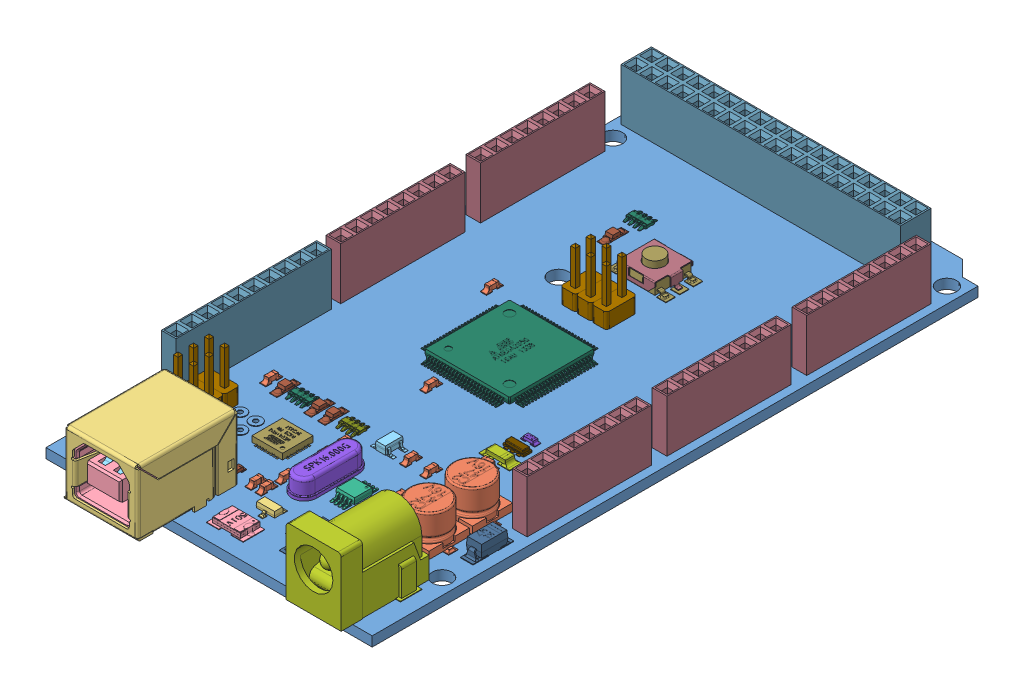
SolidWorks assembly arduino MEGA2650, configuration Default. Lengths in mm.
Overall size (53.34 15.25 107.99).
69 component instances, 33 part files, 170 mates.
Components (placement in the parent):
- MEGAboard-1: MEGAboard [Default] at origin size (53.34 1.6 101.6)
- 47uf CAP Dcase-1: 47uf CAP Dcase [Default] at (-9.144 0 -18.415) x (0 0 -1) z (1 0 0) size (6.6 5.81 8)
- USB type b-1: USB type b [Default] at (-38.02 0.43 6.35) size (14.34 15.2 16.54)
  - USB SHELL-1: USB SHELL [Default] at origin size (14.34 15.2 16.54)
  - USB core-1: USB core [Default] at origin size (11.3 10.68 15.75)
  - usb top contact-1: usb top contact [Default] at (1.25 6.09 -0.38) size (1 9.67 13.76)
  - usb btm contact-1: usb btm contact [Default] at (1.25 4.41 -0.38) size (1 6.84 11.76)
  - usb btm contact-2: usb btm contact [Default] at (-1.25 4.41 -0.38) size (1 6.84 11.76)
  - usb top contact-2: usb top contact [Default] at (-1.25 6.09 -0.38) size (1 9.67 13.76)
- power jack-1: power jack [Default] at (-7.675 0 1.905) size (11.2 15.2 15.9)
- 47uf CAP Dcase-2: 47uf CAP Dcase [Default] at (-9.144 0 -25.527) x (0 0 -1) z (1 0 0) size (6.6 5.81 8)
- crystal-1: crystal [Default] at (-26.035 0 -18.415) x (1 0 0) z (0 0 -1) size (4 5 11)
- 2pin_header__02-1: 2pin_header__02 [Default] at (-46.23 0 -15.75) size (5 11.75 2.54)
- reg-1: reg [Default] at (-17.78 0 -8.636) size (6.5 1.69 8.3)
- led-1: led [Default] at (-34.29 0 -27.94) x (0 0 1) z (-1 0 0) size (4 0.86 1.35)
- 2pin_header__02-2: 2pin_header__02 [Default] at (-30.43 0 -64.91) x (0 0 1) z (-1 0 0) size (5 11.75 2.54)
- 2pin_header__02-3: 2pin_header__02 [Default] at (-27.89 0 -64.91) x (0 0 1) z (-1 0 0) size (5 11.75 2.54)
- 2pin_header__02-4: 2pin_header__02 [Default] at (-25.35 0 -64.91) x (0 0 1) z (-1 0 0) size (5 11.75 2.54)
- 2pin_header__02-5: 2pin_header__02 [Default] at (-46.23 0 -18.29) size (5 11.75 2.54)
- 2pin_header__02-6: 2pin_header__02 [Default] at (-46.23 0 -20.83) size (5 11.75 2.54)
- atmega16u2-1: atmega16u2 [Default] at (-34.671 0.06 -20) x (1 0 0) z (0 0 -1) size (5.5 1.01 5.5)
- led-2: led [Default] at (-36.576 0 -27.94) x (0 0 -1) z (1 0 0) size (4 0.86 1.35)
- led-3: led [Default] at (-42.164 0 -27.94) x (0 0 1) z (-1 0 0) size (4 0.86 1.35)
- led-4: led [Default] at (-36.83 0 -76.2) x (0 0 1) z (-1 0 0) size (4 0.86 1.35)
- 8 PORT HEADER-3: 8 PORT HEADER [Default] at (-50.8 0 -45.72) x (0 0 -1) z (1 0 0) size (20.32 10.51 2.41)
- 8 PORT HEADER-4: 8 PORT HEADER [Default] at (-2.54 0 -27.94) x (0 0 -1) z (1 0 0) size (20.32 10.51 2.41)
- 8 PORT HEADER-6: 8 PORT HEADER [Default] at (-2.54 0 -50.8) x (0 0 -1) z (1 0 0) size (20.32 10.51 2.41)
- 10 PORT HEADER-1: 10 PORT HEADER [Default] at (-50.8 0 -18.796) x (0 0 -1) z (1 0 0) size (25.4 10.51 2.41)
- 102 RESISTOR PACK-1: 102 RESISTOR PACK [Default] at (-36.83 0 -80.645) size (3.2 0.46 3)
- 102 RESISTOR PACK-2: 102 RESISTOR PACK [Default] at (-39.37 0 -27.94) size (3.2 0.46 3)
- 103 RESISTOR PACK-3: 103 RESISTOR PACK [Default] at (-31.115 0 -27.94) size (3.2 0.46 3)
- 220 RESISTOR PACK-1: 220 RESISTOR PACK [Default] at (-37.084 0 -12.065) size (3.2 0.46 3)
- 16mhz crystal - measured-1: 16mhz crystal - measured [Default] at (-14.605 0 -38.354) size (3.4 0.8 2)
- PADS001-1: PADS001 [Default] at (-39.878 0.1 -18.288) x (-1 0 0) z (0 0 1) size (4.54 0.1 4.54)
- 603 cap on pad-1: 603 cap on pad [Default] at (-44.45 0 -27.94) x (0 0 -1) z (1 0 0) size (2.76 0.9 1.12)
- ssot3-1: ssot3 [Default] at (-25.908 0 -9.144) x (-1 0 0) z (0 0 -1) size (3 1.13 3.09)
- mf-msmf050-2-1: mf-msmf050-2 [Default] at (-26.67 0 -4.445) size (5.77 1.02 3.72)
- 603 cap on pad-2: 603 cap on pad [Default] at (-29.337 0 -24.765) x (0 0 1) z (-1 0 0) size (2.76 0.9 1.12)
- 603 cap on pad-3: 603 cap on pad [Default] at (-30.988 0 -12.065) x (0 0 -1) z (1 0 0) size (2.76 0.9 1.12)
- lmv358-1: lmv358 [Default] at (-25.146 0 -27.94) size (3.7 1.4 2.9)
- 603 cap on pad-4: 603 cap on pad [Default] at (-17.653 0 -14.351) size (2.76 0.9 1.12)
- 603 cap on pad-5: 603 cap on pad [Default] at (-29.337 0 -12.065) x (0 0 1) z (-1 0 0) size (2.76 0.9 1.12)
- 603 cap on pad-6: 603 cap on pad [Default] at (-29.337 0 -21.59) x (0 0 1) z (-1 0 0) size (2.76 0.9 1.12)
- 603 cap on pad-7: 603 cap on pad [Default] at (-29.337 0 -15.24) x (0 0 1) z (-1 0 0) size (2.76 0.9 1.12)
- 603 cap on pad-8: 603 cap on pad [Default] at (-42.291 0 -12.065) x (0 0 1) z (-1 0 0) size (2.76 0.9 1.12)
- lp2985dgkr-1: lp2985dgkr [Default] at (-21.336 0 -18.415) x (0 0 -1) z (1 0 0) size (5.85 1.1 3)
- cd1206 diode-1: cd1206 diode [Default] at (-14.605 0 -35.56) x (0 0 1) z (-1 0 0) size (2.07 0.96 5)
- cd1206 diode-2: cd1206 diode [Default] at (-46.228 0 -13.081) x (0 0 1) z (-1 0 0) size (2.07 0.96 5)
- 603 resistor-1: 603 resistor [Default] at (-29.337 0 -18.415) x (0 0 1) z (-1 0 0) size (2.36 0.61 1.03)
- blm21-1: blm21 [Default] at (-45.085 0 -8.255) x (0 0 -1) z (1 0 0) size (2.76 0.95 1.32)
- m7 diode-1: m7 diode [Default] at (-2.794 0 -21.59) x (0 0 -1) z (1 0 0) size (6.66 2.35 2.5)
- MLC0603-1: MLC0603 [Default] at (-34.29 0 -12.065) x (0 0 -1) z (1 0 0) size (2.36 0.6 1.03)
- MLC0603-2: MLC0603 [Default] at (-39.878 0 -12.065) x (0 0 -1) z (1 0 0) size (2.36 0.6 1.03)
- RESET BUTTON-1: RESET BUTTON [Default] at (-27.94 0 -74.168) x (0 0 -1) z (1 0 0) size (6.2 3.1 9.6)
  - RESET CORE-1: RESET CORE [Default] at (0 0.1 0) x (-1 0 0) z (0 0 -1) size (6.2 3.1 9.6)
  - RESET-1: RESET [Default] at (0 0.1 0) x (0 0 1) z (-1 0 0) size (7.3 2 6.2)
- 8 PORT HEADER-5: 8 PORT HEADER [Default] at (-2.54 0 -73.66) x (0 0 -1) z (1 0 0) size (20.32 10.51 2.41)
- 8 PORT HEADER-7: 8 PORT HEADER [Default] at (-50.8 0 -68.58) x (0 0 -1) z (1 0 0) size (20.32 10.51 2.41)
- 603 cap on pad-9: 603 cap on pad [Default] at (-21.59 0 -27.94) x (0 0 1) z (-1 0 0) size (2.76 0.9 1.12)
- 603 cap on pad-10: 603 cap on pad [Default] at (-18.288 0 -27.94) x (0 0 1) z (-1 0 0) size (2.76 0.9 1.12)
- 103 RESISTOR PACK-4: 103 RESISTOR PACK [Default] at (-16.51 0 -18.415) size (3.2 0.46 3)
- 603 cap on pad-11: 603 cap on pad [Default] at (-17.145 0 -21.59) x (0 0 -1) z (1 0 0) size (2.76 0.9 1.12)
- 603 cap on pad-12: 603 cap on pad [Default] at (-39.37 0 -58.928) x (0 0 1) z (-1 0 0) size (2.76 0.9 1.12)
- 603 cap on pad-13: 603 cap on pad [Default] at (-14.605 0 -33.528) size (2.76 0.9 1.12)
- 603 resistor-2: 603 resistor [Default] at (-14.605 0 -40.513) x (-1 0 0) z (0 0 -1) size (2.36 0.61 1.03)
- 603 cap on pad-14: 603 cap on pad [Default] at (-7.112 0 -38.608) x (0 0 1) z (-1 0 0) size (2.76 0.9 1.12)
- 603 cap on pad-15: 603 cap on pad [Default] at (-30.4038 0 -40.0558) x (0 0 1) z (-1 0 0) size (2.76 0.9 1.12)
- 18 X 2 ROW HEADER-1: 18 X 2 ROW HEADER [Default] at (-50.8 0 -95.25) size (45.72 10.51 4.95)
- atmega2650-16AU-1: atmega2650-16AU [Default] at (-28.3464 0.1 -50.8) x (0 0 1) z (-1 0 0) size (16.8 1.1 16.8)
Mates (geometry in assembly coordinates):
- Distance1: distance = 1.905 mm aligned: plane of power jack-1 through (-7.675 0 1.905) normal (0 0 1); plane of MEGAboard-1 through (0 0 0) normal (0 0 1)
- Coincident2: coincident aligned: plane of MEGAboard-1 through (0 0 0) normal (0 1 0); plane of power jack-1 through (-7.675 0 1.905) normal (0 1 0)
- Coincident3: coincident anti-aligned: plane of MEGAboard-1 through (0 0 0) normal (0 1 0); plane of USB type b-1/USB core-1 through (-38.02 0 6.35) normal (0 -1 0)
- Distance2: distance = 6.35 mm aligned: plane of USB type b-1/USB SHELL-1 through (-38.02 0.43 6.35) normal (0 0 1); plane of MEGAboard-1 through (0 0 0) normal (0 0 1)
- Coincident5: coincident aligned: plane of MEGAboard-1 through (0 0 0) normal (0 1 0); plane of 47uf CAP Dcase-1
- Parallel1: parallel anti-aligned: plane of MEGAboard-1 through (0 0 0) normal (0 0 1); plane of 47uf CAP Dcase-1 through (-9.144 0 -18.415) normal (0 0 -1)
- Coincident7: coincident aligned: plane of 47uf CAP Dcase-1 through (-5.844 1.5 -15.115) normal (1 0 0); plane of 47uf CAP Dcase-2 through (-5.844 1.5 -22.227) normal (1 0 0)
- Coincident8: coincident anti-aligned: plane of MEGAboard-1 through (0 0 0) normal (0 1 0); plane of 47uf CAP Dcase-2 through (-7.919 0 -25.527) normal (0 -1 0)
- Distance3: distance = 3.175 mm aligned: plane of power jack-1 through (-3.175 10.5 -1.595) normal (1 0 0); plane of MEGAboard-1 through (0 -1.6 0) normal (1 0 0)
- Distance4: distance = 32 mm aligned: plane of USB type b-1/USB SHELL-1 through (-32 0.43 6.35) normal (1 0 0); plane of MEGAboard-1 through (0 -1.6 0) normal (1 0 0)
- Coincident11: coincident anti-aligned: plane of MEGAboard-1 through (0 0 0) normal (0 1 0); plane of crystal-1 through (-26.035 0 -21.915) normal (0 -1 0)
- Concentric1: concentric aligned: cylinder of MEGAboard-1 through (-26.035 -10 -15.875) axis (0 1 0) radius 0.5; cylinder of crystal-1 through (-26.035 -2 -15.875) axis (0 1 0) radius 0.4
- Concentric2: concentric aligned: cylinder of MEGAboard-1 through (-26.035 -10 -20.955) axis (0 1 0) radius 0.5; cylinder of crystal-1 through (-26.035 -2 -20.955) axis (0 1 0) radius 0.4
- Coincident12: coincident anti-aligned: plane of MEGAboard-1 through (0 0 0) normal (0 1 0); plane of 2pin_header__02-1 through (-44.23 0 -14.98) normal (0 -1 0)
- Distance5: distance = 15.75 mm aligned: plane of 2pin_header__02-1 through (-46.23 0 -15.75) normal (0 0 1); plane of assembly through (0 0 0) normal (0 0 1)
- Distance6: distance = 46.23 mm aligned: plane of 2pin_header__02-1 through (-46.23 0 -15.75) normal (1 0 0); plane of assembly through (0 0 0) normal (1 0 0)
- Coincident15: coincident anti-aligned: plane of MEGAboard-1 through (0 0 0) normal (0 1 0); plane of 2pin_header__02-2 through (-31.2 0 -62.91) normal (0 -1 0)
- Distance7: distance = 64.91 mm aligned: plane of 2pin_header__02-2 through (-30.43 0 -64.91) normal (0 0 1); plane of assembly through (0 0 0) normal (0 0 1)
- Distance8: distance = 30.43 mm anti-aligned: plane of 2pin_header__02-2 through (-30.43 0 -64.91) normal (-1 0 0); plane of assembly through (0 0 0) normal (1 0 0)
- Coincident19: coincident anti-aligned: plane of MEGAboard-1 through (0 0 0) normal (0 1 0); plane of reg-1 through (-17.78 0 -8.636) normal (0 -1 0)
- Coincident21: coincident anti-aligned: plane of MEGAboard-1 through (0 0 0) normal (0 1 0); plane of atmega16u2-1 through (-34.671 0 -20) normal (0 -1 0)
- Distance10: distance = 20 mm anti-aligned: plane of atmega16u2-1 through (-34.671 0.06 -20) normal (0 0 -1); plane of MEGAboard-1 through (0 0 0) normal (0 0 1)
- Distance11: distance = 34.671 mm aligned: plane of atmega16u2-1; plane of MEGAboard-1 through (0 0 0) normal (1 0 0)
- Coincident25: coincident anti-aligned: plane of MEGAboard-1 through (0 0 0) normal (0 1 0); plane of led-1 through (-34.29 0 -28.94) normal (0 -1 0)
- Distance12: distance = 34.29 mm anti-aligned: plane of led-1 through (-34.29 0 -27.94) normal (-1 0 0); plane of MEGAboard-1 through (0 0 0) normal (1 0 0)
- Distance13: distance = 27.94 mm aligned: plane of led-1 through (-34.29 0 -27.94) normal (0 0 1); plane of MEGAboard-1 through (0 0 0) normal (0 0 1)
- Coincident28: coincident aligned: plane of led-2 through (-36.576 0 -26.94) normal (0 -1 0); plane of led-3 through (-42.164 0 -28.94) normal (0 -1 0)
- Coincident29: coincident anti-aligned: plane of led-1 through (-34.29 0 -27.94) normal (0 0 1); plane of led-2 through (-36.576 0 -27.94) normal (0 0 -1)
- Coincident30: coincident aligned: plane of led-1 through (-34.29 0 -27.94) normal (0 0 1); plane of led-3 through (-42.164 0 -27.94) normal (0 0 1)
- Distance14: distance = 36.576 mm aligned: plane of led-2 through (-36.576 0 -27.94) normal (1 0 0); plane of MEGAboard-1 through (0 0 0) normal (1 0 0)
- Coincident32: coincident anti-aligned: plane of MEGAboard-1 through (0 0 0) normal (0 1 0); plane of led-2 through (-36.576 0 -26.94) normal (0 -1 0)
- Distance15: distance = 42.164 mm anti-aligned: plane of led-3 through (-42.164 0 -27.94) normal (-1 0 0); plane of MEGAboard-1 through (0 0 0) normal (1 0 0)
- Coincident34: coincident anti-aligned: plane of MEGAboard-1 through (0 0 0) normal (0 1 0); plane of led-4 through (-36.83 0 -77.2) normal (0 -1 0)
- Distance16: distance = 36.83 mm anti-aligned: plane of led-4 through (-36.83 0 -76.2) normal (-1 0 0); plane of MEGAboard-1 through (0 0 0) normal (1 0 0)
- Distance17: distance = 76.2 mm aligned: plane of led-4 through (-36.83 0 -76.2) normal (0 0 1); plane of MEGAboard-1 through (0 0 0) normal (0 0 1)
- Coincident37: coincident aligned: plane of MEGAboard-1 through (0 0 0) normal (0 1 0); plane of 8 PORT HEADER-4
- Coincident38: coincident aligned: plane of MEGAboard-1 through (0 0 0) normal (0 1 0); plane of 8 PORT HEADER-3
- Parallel2: parallel aligned: plane of MEGAboard-1 through (0 0 0) normal (1 0 0); plane of 8 PORT HEADER-4 through (-2.54 0 -27.94) normal (1 0 0)
- Parallel3: parallel aligned: plane of MEGAboard-1 through (0 0 0) normal (1 0 0); plane of 8 PORT HEADER-3 through (-50.8 0 -45.72) normal (1 0 0)
- Concentric5: concentric aligned: cylinder of MEGAboard-1 through (-2.54 -1.65 -27.94) axis (0 1 0) radius 0.4; line of 8 PORT HEADER-4 through (-2.54 -2.5255 -27.94) axis (0 1 0)
- Concentric6: concentric aligned: cylinder of MEGAboard-1 through (-50.8 -1.65 -45.72) axis (0 1 0) radius 0.4; line of 8 PORT HEADER-3 through (-50.8 -2.5255 -45.72) axis (0 1 0)
- Coincident43: coincident aligned: plane of MEGAboard-1 through (0 0 0) normal (0 1 0); plane of 10 PORT HEADER-1
- Coincident44: coincident aligned: plane of MEGAboard-1 through (0 0 0) normal (0 1 0); plane of 8 PORT HEADER-6
- Parallel4: parallel aligned: plane of MEGAboard-1 through (0 0 0) normal (1 0 0); plane of 8 PORT HEADER-6 through (-2.54 0 -50.8) normal (1 0 0)
- Parallel5: parallel aligned: plane of MEGAboard-1 through (0 0 0) normal (1 0 0); plane of 10 PORT HEADER-1 through (-50.8 0 -18.796) normal (1 0 0)
- Concentric7: concentric aligned: cylinder of MEGAboard-1 through (-50.8 -1.65 -18.796) axis (0 1 0) radius 0.4; line of 10 PORT HEADER-1 through (-50.8 -2.5255 -18.796) axis (0 1 0)
- Concentric9: concentric aligned: cylinder of MEGAboard-1 through (-2.54 -1.65 -50.8) axis (0 1 0) radius 0.4; line of 8 PORT HEADER-6 through (-2.54 -2.5255 -50.8) axis (0 1 0)
- Distance18: distance = 8.636 mm: plane of reg-1 through (-17.78 0 -8.636) normal (0 0 1); line of MEGAboard-1 through (-53.34 0 0) axis (1 0 0)
- Distance19: distance = 17.78 mm aligned: plane of reg-1 through (-17.78 0 -8.636) normal (1 0 0); plane of MEGAboard-1 through (0 0 0) normal (1 0 0)
- Coincident55: coincident anti-aligned: plane of MEGAboard-1 through (0 0 0) normal (0 1 0); plane of 102 RESISTOR PACK-1 through (-37.03 0 -81.345) normal (0 -1 0)
- Distance20: distance = 36.83 mm aligned: plane of 102 RESISTOR PACK-1 through (-36.83 0 -80.645) normal (1 0 0); plane of MEGAboard-1 through (0 0 0) normal (1 0 0)
- Distance21: distance = 80.645 mm aligned: plane of 102 RESISTOR PACK-1 through (-36.83 0 -80.645) normal (0 0 1); plane of MEGAboard-1 through (0 0 0) normal (0 0 1)
- Coincident58: coincident aligned: plane of 102 RESISTOR PACK-2 through (-39.37 0 -27.94) normal (0 1 0); plane of 103 RESISTOR PACK-3 through (-31.115 0 -27.94) normal (0 1 0)
- Coincident59: coincident aligned: plane of MEGAboard-1 through (0 0 0) normal (0 1 0); plane of 103 RESISTOR PACK-3 through (-31.115 0 -27.94) normal (0 1 0)
- Coincident60: coincident aligned: plane of 102 RESISTOR PACK-2 through (-39.37 0 -27.94) normal (0 0 1); plane of 103 RESISTOR PACK-3 through (-31.115 0 -27.94) normal (0 0 1)
- Distance22: distance = 31.115 mm aligned: plane of 103 RESISTOR PACK-3 through (-31.115 0 -27.94) normal (1 0 0); plane of MEGAboard-1 through (0 0 0) normal (1 0 0)
- Distance23: distance = 39.37 mm aligned: plane of 102 RESISTOR PACK-2 through (-39.37 0 -27.94) normal (1 0 0); plane of MEGAboard-1 through (0 0 0) normal (1 0 0)
- Distance24: distance = 27.94 mm aligned: plane of 102 RESISTOR PACK-2 through (-39.37 0 -27.94) normal (0 0 1); plane of MEGAboard-1 through (0 0 0) normal (0 0 1)
- Distance25: distance = 12.065 mm aligned: plane of 220 RESISTOR PACK-1 through (-37.084 0 -12.065) normal (0 0 1); plane of MEGAboard-1 through (0 0 0) normal (0 0 1)
- Distance26: distance = 37.084 mm aligned: plane of 220 RESISTOR PACK-1 through (-37.084 0 -12.065) normal (1 0 0); plane of MEGAboard-1 through (0 0 0) normal (1 0 0)
- Coincident66: coincident aligned: plane of MEGAboard-1 through (0 0 0) normal (0 1 0); plane of 220 RESISTOR PACK-1 through (-37.084 0 -12.065) normal (0 1 0)
- Coincident67: coincident anti-aligned: plane of MEGAboard-1 through (0 0 0) normal (0 1 0); plane of 16mhz crystal - measured-1 through (-14.605 0 -38.354) normal (0 -1 0)
- Distance27: distance = 14.605 mm aligned: plane of 16mhz crystal - measured-1 through (-14.605 0 -38.354) normal (1 0 0); plane of MEGAboard-1 through (0 0 0) normal (1 0 0)
- Distance28: distance = 38.354 mm aligned: plane of 16mhz crystal - measured-1 through (-14.605 0 -38.354) normal (0 0 1); plane of MEGAboard-1 through (0 0 0) normal (0 0 1)
- Coincident70: coincident anti-aligned: plane of MEGAboard-1 through (0 0 0) normal (0 1 0); plane of PADS001-1 through (-42.418 0 -18.288) normal (0 -1 0)
- Distance29: distance = 18.288 mm aligned: plane of PADS001-1 through (-39.878 0.1 -18.288) normal (0 0 1); plane of MEGAboard-1 through (0 0 0) normal (0 0 1)
- Distance30: distance = 39.878 mm anti-aligned: plane of PADS001-1; plane of MEGAboard-1 through (0 0 0) normal (1 0 0)
- Distance31: distance = 4.445 mm aligned: plane of mf-msmf050-2-1 through (-26.67 0 -4.445) normal (0 0 1); plane of MEGAboard-1 through (0 0 0) normal (0 0 1)
- Distance32: distance = 26.67 mm aligned: plane of mf-msmf050-2-1 through (-26.67 0 -4.445) normal (1 0 0); plane of MEGAboard-1 through (0 0 0) normal (1 0 0)
- Coincident72: coincident aligned: plane of MEGAboard-1 through (0 0 0) normal (0 1 0); plane of mf-msmf050-2-1 through (-26.67 0 -4.445) normal (0 1 0)
- Distance33: distance = 9.144 mm anti-aligned: plane of MEGAboard-1 through (0 0 0) normal (0 0 1); plane of ssot3-1 through (-25.908 0 -9.144) normal (0 0 -1)
- Distance78: distance = 0.762 mm anti-aligned: plane of ssot3-1 through (-25.908 0 -9.144) normal (-1 0 0); plane of mf-msmf050-2-1 through (-26.67 0 -4.445) normal (1 0 0)
- Coincident75: coincident aligned: plane of MEGAboard-1 through (0 0 0) normal (0 1 0); plane of ssot3-1
- Coincident76: coincident anti-aligned: plane of led-1 through (-34.29 0 -27.94) normal (0 0 1); plane of 603 cap on pad-1 through (-44.45 0 -27.94) normal (0 0 -1)
- Coincident77: coincident aligned: plane of MEGAboard-1 through (0 0 0) normal (0 1 0); plane of 603 cap on pad-1
- Distance34: distance = 44.45 mm aligned: plane of 603 cap on pad-1 through (-44.45 0 -27.94) normal (1 0 0); plane of MEGAboard-1 through (0 0 0) normal (1 0 0)
- Coincident79: coincident aligned: plane of 603 cap on pad-2; plane of 603 cap on pad-3
- Coincident81: coincident aligned: plane of MEGAboard-1 through (0 0 0) normal (0 1 0); plane of 603 cap on pad-2
- Distance65: distance = 24.765 mm aligned: plane of 603 cap on pad-2 through (-29.337 0 -24.765) normal (0 0 1); plane of MEGAboard-1 through (0 0 0) normal (0 0 1)
- Distance36: distance = 29.337 mm anti-aligned: plane of 603 cap on pad-2 through (-29.337 0 -24.765) normal (-1 0 0); plane of MEGAboard-1 through (0 0 0) normal (1 0 0)
- Distance37: distance = 30.988 mm aligned: plane of 603 cap on pad-3 through (-30.988 0 -12.065) normal (1 0 0); plane of MEGAboard-1 through (0 0 0) normal (1 0 0)
- Distance38: distance = 27.94 mm aligned: plane of MEGAboard-1 through (0 0 0) normal (0 0 1); plane of lmv358-1 through (-25.146 0 -27.94) normal (0 0 1)
- Distance39: distance = 21.971 mm anti-aligned: plane of ?; plane of MEGAboard-1 through (0 0 0) normal (0 0 1)
- Coincident88: coincident aligned: plane of MEGAboard-1 through (0 0 0) normal (0 1 0); plane of lmv358-1 through (-25.146 0 -27.94) normal (0 1 0)
- Distance40: distance = 14.351 mm aligned: plane of 603 cap on pad-4 through (-17.653 0 -14.351) normal (0 0 1); plane of MEGAboard-1 through (0 0 0) normal (0 0 1)
- Distance41: distance = 17.653 mm aligned: plane of 603 cap on pad-4 through (-17.653 0 -14.351) normal (1 0 0); plane of MEGAboard-1 through (0 0 0) normal (1 0 0)
- Coincident91: coincident aligned: plane of MEGAboard-1 through (0 0 0) normal (0 1 0); plane of 603 cap on pad-4 through (-17.653 0 -14.351) normal (0 1 0)
- Coincident92: coincident aligned: plane of MEGAboard-1 through (0 0 0) normal (0 1 0); plane of 603 cap on pad-7
- Coincident93: coincident aligned: plane of MEGAboard-1 through (0 0 0) normal (0 1 0); plane of 603 cap on pad-6
- Coincident94: coincident aligned: plane of 603 cap on pad-5; plane of MEGAboard-1 through (0 0 0) normal (0 1 0)
- Coincident95: coincident aligned: plane of 603 cap on pad-8; plane of MEGAboard-1 through (0 0 0) normal (0 1 0)
- Coincident96: coincident aligned: plane of 603 cap on pad-7 through (-29.337 0 -15.24) normal (-1 0 0); plane of 603 cap on pad-6 through (-29.337 0 -21.59) normal (-1 0 0)
- Distance42: distance = 29.337 mm anti-aligned: plane of 603 cap on pad-7 through (-29.337 0 -15.24) normal (-1 0 0); plane of MEGAboard-1 through (0 0 0) normal (1 0 0)
- Distance43: distance = 21.59 mm: plane of 603 cap on pad-6 through (-29.337 0 -21.59) normal (0 0 1); line of MEGAboard-1 through (-53.34 0 0) axis (1 0 0)
- Distance44: distance = 15.24 mm aligned: plane of 603 cap on pad-7 through (-29.337 0 -15.24) normal (0 0 1); plane of MEGAboard-1 through (0 0 0) normal (0 0 1)
- Distance45: distance = 29.337 mm anti-aligned: plane of 603 cap on pad-5 through (-29.337 0 -12.065) normal (-1 0 0); plane of MEGAboard-1 through (0 0 0) normal (1 0 0)
- Distance46: distance = 12.065 mm aligned: plane of 603 cap on pad-5 through (-29.337 0 -12.065) normal (0 0 1); plane of MEGAboard-1 through (0 0 0) normal (0 0 1)
- Distance47: distance = 42.291 mm anti-aligned: plane of 603 cap on pad-8 through (-42.291 0 -12.065) normal (-1 0 0); plane of MEGAboard-1 through (0 0 0) normal (1 0 0)
- Distance48: distance = 12.065 mm aligned: plane of 603 cap on pad-8 through (-42.291 0 -12.065) normal (0 0 1); plane of MEGAboard-1 through (0 0 0) normal (0 0 1)
- Distance49: distance = 21.336 mm aligned: plane of lp2985dgkr-1 through (-21.336 0 -18.415) normal (1 0 0); plane of MEGAboard-1 through (0 0 0) normal (1 0 0)
- Distance50: distance = 18.415 mm anti-aligned: plane of lp2985dgkr-1 through (-21.336 0 -18.415) normal (0 0 -1); plane of MEGAboard-1 through (0 0 0) normal (0 0 1)
- Coincident99: coincident aligned: plane of MEGAboard-1 through (0 0 0) normal (0 1 0); plane of lp2985dgkr-1
- Distance51: distance = 14.605 mm anti-aligned: plane of cd1206 diode-1 through (-14.605 0 -35.56) normal (-1 0 0); plane of MEGAboard-1 through (0 0 0) normal (1 0 0)
- Distance52: distance = 35.56 mm aligned: plane of cd1206 diode-1 through (-14.605 0 -35.56) normal (0 0 1); plane of MEGAboard-1 through (0 0 0) normal (0 0 1)
- Coincident102: coincident aligned: plane of MEGAboard-1 through (0 0 0) normal (0 1 0); plane of cd1206 diode-1
- Distance53: distance = 46.228 mm anti-aligned: plane of cd1206 diode-2 through (-46.228 0 -13.081) normal (-1 0 0); plane of MEGAboard-1 through (0 0 0) normal (1 0 0)
- Distance54: distance = 13.081 mm aligned: plane of MEGAboard-1 through (0 0 0) normal (0 0 1); plane of cd1206 diode-2 through (-46.228 0 -13.081) normal (0 0 1)
- Coincident105: coincident aligned: plane of MEGAboard-1 through (0 0 0) normal (0 1 0); plane of cd1206 diode-2
- Distance55: distance = 29.337 mm anti-aligned: plane of 603 resistor-1 through (-29.337 0 -18.415) normal (-1 0 0); plane of MEGAboard-1 through (0 0 0) normal (1 0 0)
- Distance56: distance = 18.415 mm aligned: plane of 603 resistor-1 through (-29.337 0 -18.415) normal (0 0 1); plane of MEGAboard-1 through (0 0 0) normal (0 0 1)
- Coincident108: coincident aligned: plane of MEGAboard-1 through (0 0 0) normal (0 1 0); plane of 603 resistor-1
- Distance57: distance = 8.255 mm anti-aligned: plane of blm21-1 through (-45.085 0 -8.255) normal (0 0 -1); plane of MEGAboard-1 through (0 0 0) normal (0 0 1)
- Distance58: distance = 45.085 mm aligned: plane of blm21-1 through (-45.085 0 -8.255) normal (1 0 0); plane of MEGAboard-1 through (0 0 0) normal (1 0 0)
- Distance59: distance = 21.59 mm anti-aligned: plane of m7 diode-1 through (-2.794 0 -21.59) normal (0 0 -1); plane of MEGAboard-1 through (0 0 0) normal (0 0 1)
- Distance60: distance = 2.794 mm aligned: plane of m7 diode-1 through (-2.794 0 -21.59) normal (1 0 0); plane of MEGAboard-1 through (0 0 0) normal (1 0 0)
- Coincident113: coincident aligned: plane of MEGAboard-1 through (0 0 0) normal (0 1 0); plane of m7 diode-1
- Coincident114: coincident anti-aligned: plane of 220 RESISTOR PACK-1 through (-37.084 0 -12.065) normal (0 0 1); plane of MLC0603-1 through (-34.29 0 -12.065) normal (0 0 -1)
- Distance61: distance = 34.29 mm aligned: plane of MLC0603-1 through (-34.29 0 -12.065) normal (1 0 0); plane of MEGAboard-1 through (0 0 0) normal (1 0 0)
- Coincident115: coincident aligned: plane of MEGAboard-1 through (0 0 0) normal (0 1 0); plane of MLC0603-1
- Coincident116: coincident aligned: plane of MEGAboard-1 through (0 0 0) normal (0 1 0); plane of blm21-1
- Coincident117: coincident anti-aligned: plane of 220 RESISTOR PACK-1 through (-37.084 0 -12.065) normal (0 0 1); plane of MLC0603-2 through (-39.878 0 -12.065) normal (0 0 -1)
- Coincident118: coincident aligned: plane of MEGAboard-1 through (0 0 0) normal (0 1 0); plane of MLC0603-2
- Distance62: distance = 39.878 mm aligned: plane of MLC0603-2 through (-39.878 0 -12.065) normal (1 0 0); plane of MEGAboard-1 through (0 0 0) normal (1 0 0)
- Coincident122: coincident aligned: plane of MEGAboard-1 through (0 0 0) normal (0 1 0); plane of RESET BUTTON-1
- Concentric10: concentric aligned: cylinder of MEGAboard-1 through (-2.54 -1.65 -73.66) axis (0 1 0) radius 0.4; line of 8 PORT HEADER-5 through (-2.54 -2.5255 -73.66) axis (0 1 0)
- Coincident124: coincident anti-aligned: plane of MEGAboard-1 through (0 0 0) normal (0 1 0); plane of 8 PORT HEADER-5 through (-2.54 0 -73.66) normal (0 -1 0)
- Parallel6: parallel aligned: plane of MEGAboard-1 through (0 0 0) normal (1 0 0); plane of 8 PORT HEADER-5 through (-1.335 8.51 -72.39) normal (1 0 0)
- Concentric11: concentric aligned: cylinder of MEGAboard-1 through (-50.8 -1.65 -68.58) axis (0 1 0) radius 0.4; line of 8 PORT HEADER-7 through (-50.8 -2.5255 -68.58) axis (0 1 0)
- Parallel7: parallel aligned: plane of MEGAboard-1 through (0 0 0) normal (1 0 0); plane of 8 PORT HEADER-7 through (-49.595 8.51 -67.31) normal (1 0 0)
- Coincident128: coincident anti-aligned: plane of MEGAboard-1 through (0 0 0) normal (0 1 0); plane of 8 PORT HEADER-7 through (-50.8 0 -68.58) normal (0 -1 0)
- Distance63: distance = 27.94 mm aligned: plane of RESET BUTTON-1; plane of MEGAboard-1 through (0 0 0) normal (1 0 0)
- Distance64: distance = 74.168 mm anti-aligned: plane of RESET BUTTON-1 through (-27.94 0 -74.168) normal (0 0 -1); plane of MEGAboard-1 through (0 0 0) normal (0 0 1)
- Coincident131: coincident anti-aligned: plane of 603 cap on pad-3 through (-30.988 0 -12.065) normal (0 0 -1); plane of 603 cap on pad-5 through (-29.337 0 -12.065) normal (0 0 1)
- Distance66: distance = 25.146 mm aligned: plane of lmv358-1 through (-25.146 0 -27.94) normal (1 0 0); plane of MEGAboard-1 through (0 0 0) normal (1 0 0)
- Distance67: distance = 9.144 mm aligned: plane of 47uf CAP Dcase-2 through (-9.144 0 -25.527) normal (1 0 0); plane of MEGAboard-1 through (0 0 0) normal (1 0 0)
- Distance68: distance = 25.527 mm anti-aligned: plane of 47uf CAP Dcase-2 through (-9.144 0 -25.527) normal (0 0 -1); plane of MEGAboard-1 through (0 0 0) normal (0 0 1)
- Distance69: distance = 18.415 mm anti-aligned: plane of 47uf CAP Dcase-1 through (-9.144 0 -18.415) normal (0 0 -1); plane of MEGAboard-1 through (0 0 0) normal (0 0 1)
- Coincident136: coincident aligned: plane of 603 cap on pad-9 through (-21.59 0 -27.94) normal (0 0 1); plane of 603 cap on pad-10 through (-18.288 0 -27.94) normal (0 0 1)
- Distance72: distance = 3.302 mm aligned: plane of 603 cap on pad-9 through (-21.59 0 -27.94) normal (-1 0 0); plane of 603 cap on pad-10 through (-18.288 0 -27.94) normal (-1 0 0)
- Coincident143: coincident aligned: plane of 603 cap on pad-9; plane of 603 cap on pad-10
- Coincident144: coincident aligned: plane of MEGAboard-1 through (0 0 0) normal (0 1 0); plane of 603 cap on pad-9
- Coincident145: coincident anti-aligned: plane of 603 cap on pad-1 through (-44.45 0 -27.94) normal (0 0 -1); plane of 603 cap on pad-9 through (-21.59 0 -27.94) normal (0 0 1)
- Distance73: distance = 21.59 mm anti-aligned: plane of 603 cap on pad-9 through (-21.59 0 -27.94) normal (-1 0 0); plane of MEGAboard-1 through (0 0 0) normal (1 0 0)
- Coincident147: coincident aligned: plane of MEGAboard-1 through (0 0 0) normal (0 1 0); plane of 103 RESISTOR PACK-4 through (-16.51 0 -18.415) normal (0 1 0)
- Distance74: distance = 16.51 mm aligned: plane of 103 RESISTOR PACK-4 through (-16.51 0 -18.415) normal (1 0 0); plane of MEGAboard-1 through (0 0 0) normal (1 0 0)
- Distance75: distance = 18.415 mm aligned: plane of 103 RESISTOR PACK-4 through (-16.51 0 -18.415) normal (0 0 1); plane of MEGAboard-1 through (0 0 0) normal (0 0 1)
- Coincident150: coincident aligned: plane of MEGAboard-1 through (0 0 0) normal (0 1 0); plane of 603 cap on pad-11
- Distance76: distance = 17.145 mm aligned: plane of 603 cap on pad-11 through (-17.145 0 -21.59) normal (1 0 0); plane of MEGAboard-1 through (0 0 0) normal (1 0 0)
- Distance77: distance = 21.59 mm anti-aligned: plane of 603 cap on pad-11 through (-17.145 0 -21.59) normal (0 0 -1); plane of MEGAboard-1 through (0 0 0) normal (0 0 1)
- Coincident154: coincident aligned: plane of MEGAboard-1 through (0 0 0) normal (0 1 0); plane of 603 cap on pad-12
- Distance79: distance = 39.37 mm anti-aligned: plane of 603 cap on pad-12 through (-39.37 0 -58.928) normal (-1 0 0); plane of MEGAboard-1 through (0 0 0) normal (1 0 0)
- Distance80: distance = 58.928 mm aligned: plane of 603 cap on pad-12 through (-39.37 0 -58.928) normal (0 0 1); plane of MEGAboard-1 through (0 0 0) normal (0 0 1)
- Coincident155: coincident aligned: plane of 603 cap on pad-13 through (-14.605 0 -33.528) normal (0 1 0); plane of 603 resistor-2
- Coincident156: coincident anti-aligned: plane of 603 cap on pad-13 through (-14.605 0 -33.528) normal (1 0 0); plane of 603 resistor-2 through (-14.605 0 -40.513) normal (-1 0 0)
- Distance81: distance = 6.985 mm anti-aligned: plane of 603 cap on pad-13 through (-14.605 0 -33.528) normal (0 0 1); plane of 603 resistor-2 through (-14.605 0 -40.513) normal (0 0 -1)
- Distance82: distance = 33.528 mm aligned: plane of 603 cap on pad-13 through (-14.605 0 -33.528) normal (0 0 1); plane of MEGAboard-1 through (0 0 0) normal (0 0 1)
- Distance83: distance = 14.605 mm aligned: plane of 603 cap on pad-13 through (-14.605 0 -33.528) normal (1 0 0); plane of MEGAboard-1 through (0 0 0) normal (1 0 0)
- Coincident160: coincident aligned: plane of MEGAboard-1 through (0 0 0) normal (0 1 0); plane of 603 resistor-2
- Coincident161: coincident aligned: plane of MEGAboard-1 through (0 0 0) normal (0 1 0); plane of 603 cap on pad-14
- Distance84: distance = 7.112 mm anti-aligned: plane of 603 cap on pad-14 through (-7.112 0 -38.608) normal (-1 0 0); plane of MEGAboard-1 through (0 0 0) normal (1 0 0)
- Distance85: distance = 38.608 mm aligned: plane of 603 cap on pad-14 through (-7.112 0 -38.608) normal (0 0 1); plane of MEGAboard-1 through (0 0 0) normal (0 0 1)
- Coincident164: coincident aligned: plane of MEGAboard-1 through (0 0 0) normal (0 1 0); plane of 603 cap on pad-15
- Distance86: distance = 30.4038 mm anti-aligned: plane of 603 cap on pad-15 through (-30.4038 0 -40.0558) normal (-1 0 0); plane of MEGAboard-1 through (0 0 0) normal (1 0 0)
- Distance87: distance = 40.0558 mm aligned: plane of 603 cap on pad-15 through (-30.4038 0 -40.0558) normal (0 0 1); plane of MEGAboard-1 through (0 0 0) normal (0 0 1)
- Concentric12: concentric anti-aligned: cylinder of MEGAboard-1 through (-50.8 -10 -96.52) axis (0 1 0) radius 0.4; cylinder of 18 X 2 ROW HEADER-1 through (-50.8 -1.55 -96.52) axis (0 -1 0) radius 0.75
- Parallel8: parallel anti-aligned: plane of MEGAboard-1 through (0 0 0) normal (0 0 1); plane of 18 X 2 ROW HEADER-1 through (-52.07 8.51 -97.725) normal (0 0 -1)
- Coincident169: coincident anti-aligned: plane of MEGAboard-1 through (0 0 0) normal (0 1 0); plane of 18 X 2 ROW HEADER-1 through (-50.8 0 -95.25) normal (0 -1 0)
- Distance88: distance = 50.8 mm aligned: plane of MEGAboard-1 through (0 0 0) normal (0 0 1); plane of atmega2650-16AU-1 through (-28.3464 0.1 -50.8) normal (0 0 1)
- Distance89: distance = 28.3464 mm anti-aligned: plane of atmega2650-16AU-1 through (-28.3464 0.1 -50.8) normal (-1 0 0); plane of MEGAboard-1 through (0 0 0) normal (1 0 0)
- Coincident172: coincident anti-aligned: plane of MEGAboard-1 through (0 0 0) normal (0 1 0); plane of atmega2650-16AU-1 through (-35.3464 0 -49.15) normal (0 -1 0)
